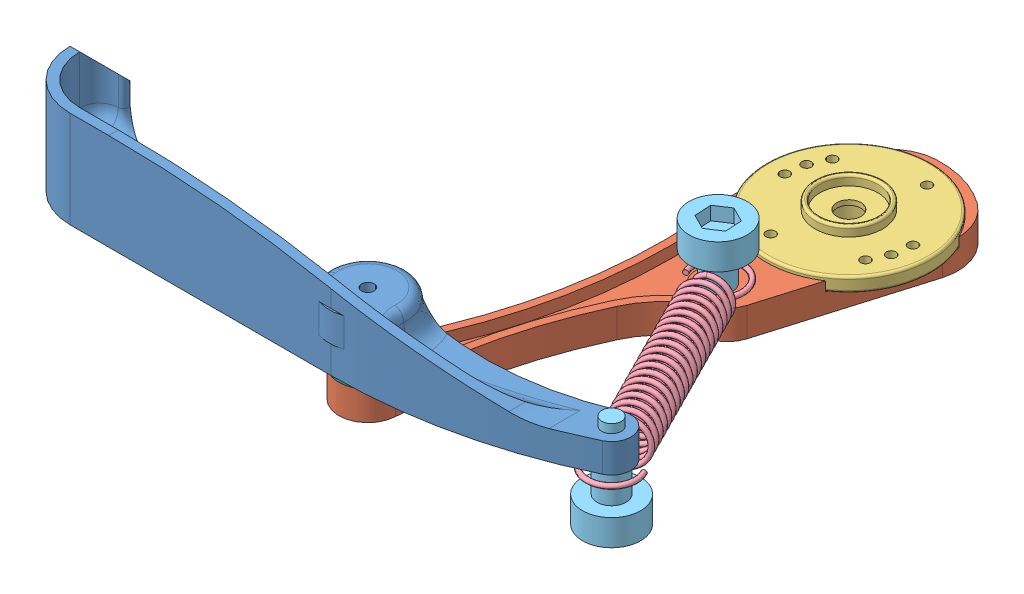
SolidWorks assembly AssemblyLeg_v2_left, configuration Default. Lengths in mm.
Overall size (58.7 15.8 54.03).
7 component instances, 6 part files, 13 mates.
Components (placement in the parent):
- LowerLeg_v2_left-1: LowerLeg_v2_left [Standard] at (-46.982 -8.259 12.3103) size (57 10 9.24)
- UpperLeg_v2_left-1: UpperLeg_v2_left [Standard] at (-2.5862 -3.259 -29.832) x (-0.284896 0 0.958558) z (0 -1 0) size (52.5 13 3)
- HS-81MG_horn-1: HS-81MG_horn [Default] at (-2.5862 -2.759 -29.832) x (-0.284896 0 0.958558) z (0 -1 0) size (17 17 5)
- spring-2: spring [Default] at (-2.1428 -2.8777 -14.7648) x (0 1 0) z (0.451588 0 0.892227) size (5 5.5 30.5)
- Schraube-2: Schraube [Standard] at (-3.2717 -0.159 -16.9953) x (0 -1 0) z (-0.448796 0 0.893634) size (9.7 6 6)
- Schraube-3: Schraube [Standard] at (8.018 -5.359 5.3103) x (0 1 0) z (0.208882 0 0.977941) size (9.7 6 6)
- spacerM3_1mm-1: spacerM3_1mm [Default] at (-13.982 -3.259 8.5103) x (1 0 0) z (0 1 0) size (6 6 1)
Mates (geometry in assembly coordinates):
- Concentric1: concentric aligned: cylinder of UpperLeg_v2_left-1 through (-2.5862 -6.259 -29.832) axis (0 1 0) radius 4; cylinder of HS-81MG_horn-1 through (-2.5862 -6.759 -29.832) axis (0 1 0) radius 4
- Coincident1: coincident anti-aligned: plane of UpperLeg_v2_left-1 through (-2.5862 -4.259 -29.832) normal (0 1 0); plane of HS-81MG_horn-1 through (-2.5862 -4.259 -29.832) normal (0 -1 0)
- Concentric2: concentric aligned: cylinder of UpperLeg_v2_left-1 through (-4.438 -3.259 -23.6014) axis (0 1 0) radius 0.5; cylinder of HS-81MG_horn-1 through (-4.438 -3.259 -23.6014) axis (0 1 0) radius 0.5
- Concentric3: concentric aligned: cylinder of LowerLeg_v2_left-1 through (-13.982 -8.259 8.5103) axis (0 1 0) radius 0.65; cylinder of UpperLeg_v2_left-1 through (-13.982 -6.259 8.5103) axis (0 1 0) radius 0.1
- Concentric4: concentric aligned: cylinder of UpperLeg_v2_left-1 through (-3.2717 -3.259 -16.9953) axis (0 1 0) radius 1; circle of spring-2
- Concentric5: concentric aligned: cylinder of UpperLeg_v2_left-1 through (-3.2717 -3.259 -16.9953) axis (0 1 0) radius 1; cylinder of Schraube-2 through (-3.2717 -0.159 -16.9953) axis (0 1 0) radius 1
- Coincident4: coincident anti-aligned: plane of UpperLeg_v2_left-1 through (16.0656 -3.259 -39.9369) normal (0 1 0); plane of Schraube-2 through (-1.9313 -3.259 -16.3221) normal (0 -1 0)
- Concentric6: concentric aligned: cylinder of LowerLeg_v2_left-1 through (8.018 -8.259 5.3103) axis (0 1 0) radius 1; circle of spring-2
- Concentric8: concentric anti-aligned: cylinder of LowerLeg_v2_left-1 through (8.018 -8.259 5.3103) axis (0 1 0) radius 1; cylinder of Schraube-3 through (8.018 -5.359 5.3103) axis (0 -1 0) radius 1
- Coincident6: coincident anti-aligned: plane of LowerLeg_v2_left-1 through (-16.982 -2.259 7.8103) normal (0 -1 0); plane of Schraube-3 through (6.551 -2.259 5.6237) normal (0 1 0)
- Concentric9: concentric anti-aligned: cylinder of LowerLeg_v2_left-1 through (-13.982 -8.259 8.5103) axis (0 1 0) radius 0.65; cylinder of spacerM3_1mm-1 through (-13.982 -2.259 8.5103) axis (0 -1 0) radius 1.5
- Coincident7: coincident anti-aligned: plane of LowerLeg_v2_left-1 through (-16.982 -2.259 7.8103) normal (0 -1 0); plane of spacerM3_1mm-1 through (-13.982 -2.259 8.5103) normal (0 1 0)
- Coincident8: coincident anti-aligned: plane of UpperLeg_v2_left-1 through (16.0656 -3.259 -39.9369) normal (0 1 0); plane of spacerM3_1mm-1 through (-13.982 -3.259 8.5103) normal (0 -1 0)
